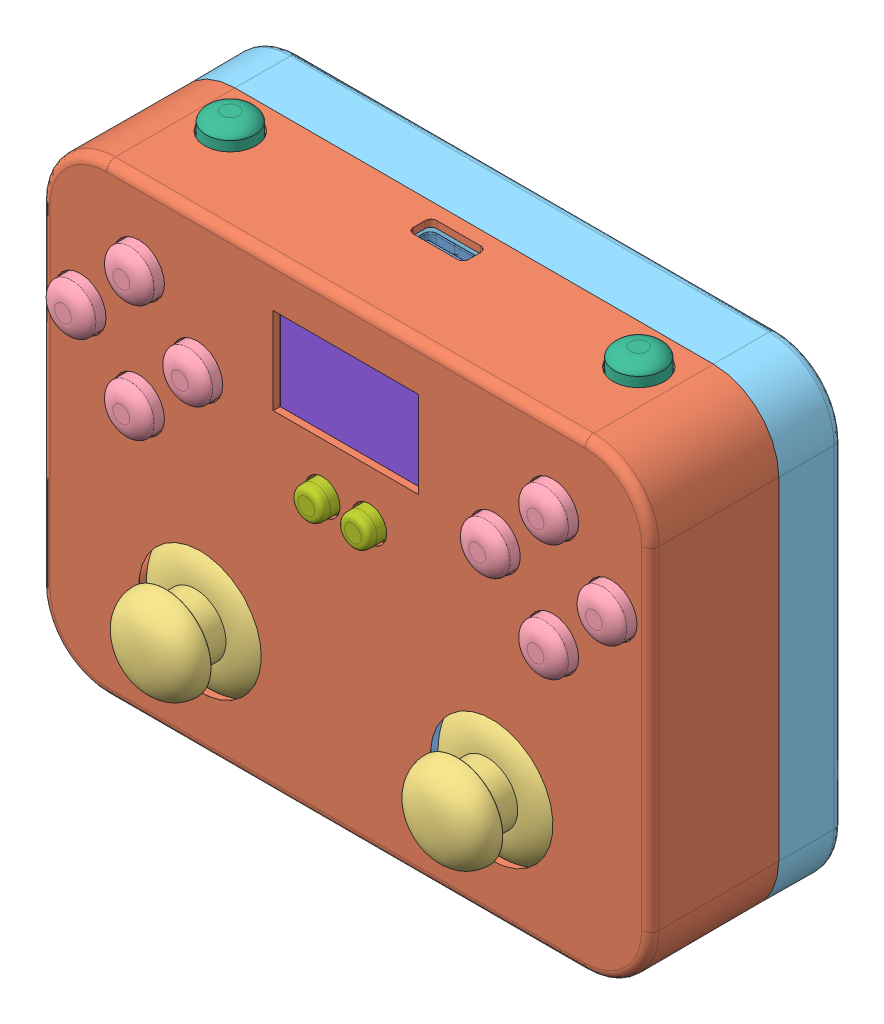
SolidWorks assembly 装配体2, configuration 默认. Lengths in mm.
Overall size (104.4 82.4 43.8).
18 component instances, 8 part files, 42 mates.
Components (placement in the parent):
- PCB2-1: PCB2 [默认] at (-22.2007 6.6699 94.0792) size (100.01 75.97 27.34)
- 上盖-1: 上盖 [默认] at (-22.2007 6.6699 113.2792) x (-1 0 0) z (0 -1 0) size (104.4 22.01 79.4)
- 摇杆-1: 摇杆 [Default] at (-47.2006 -16.3615 106.0792) x (-0.808062 -0.589097 0) z (0 0 1) size (26 26 18)
- 按钮-1: 按钮 [Default] at (-57.7007 30.6699 116.2792) x (-0.814442 0.580245 0) z (0 0 -1) size (11 8.3 17.2)
- 摇杆-2: 摇杆 [Default] at (2.7994 -16.3615 106.0792) x (0.828783 0.55957 0) z (0 0 1) size (26 26 18)
- 按钮-2: 按钮 [Default] at (13.2993 30.6699 116.2792) x (0 1 0) z (0 0 -1) size (11 8.3 17.2)
- 按钮-3: 按钮 [Default] at (-67.7007 20.6699 116.2792) x (-1 0 0) z (0 0 -1) size (11 8.3 17.2)
- 按钮-4: 按钮 [Default] at (13.2993 10.6699 116.2792) x (0 -1 0) z (0 0 -1) size (11 8.3 17.2)
- 按钮-5: 按钮 [Default] at (-57.7007 10.6699 116.2792) x (0 -1 0) z (0 0 -1) size (11 8.3 17.2)
- 按钮-6: 按钮 [Default] at (23.2993 20.6699 116.2792) x (-1 0 0) z (0 0 -1) size (11 8.3 17.2)
- 按钮-7: 按钮 [Default] at (-47.7007 20.6699 116.2792) x (-1 0 0) z (0 0 -1) size (11 8.3 17.2)
- 按钮-8: 按钮 [Default] at (3.2993 20.6699 116.2792) x (-1 0 0) z (0 0 -1) size (11 8.3 17.2)
- 后盖-1: 后盖 [默认] at (-22.2007 6.6699 80.2792) x (1 0 0) z (0 -1 0) size (104.4 12.2 79.4)
- 按钮2-1: 按钮2 [Default] at (12.7992 46.8699 98.0792) x (1 0 0) z (0 -1 0) size (13 8.3 5.4)
- 按钮2-3: 按钮2 [Default] at (-57.2006 46.8699 98.0792) x (0.990267 0 -0.139181) z (0 -1 0) size (13 8.3 5.4)
- 按钮3-1: 按钮3 [Default] at (-26.2007 12.6699 116.0792) x (0 -1 0) z (0 0 -1) size (8 5.4 17)
- 按钮3-4: 按钮3 [Default] at (-18.2007 12.6699 116.0792) x (0 -1 0) z (0 0 -1) size (8 5.4 17)
- 屏幕-1: 屏幕 [默认] at (-20.7557 28.6699 110.4792) x (0 1 0) z (0 0 1) size (17.6 31 1.6)
Mates (geometry in assembly coordinates):
- 平行1: parallel aligned: plane of 上盖-1 through (-63.2007 32.6699 113.2792) normal (0 0 1); plane of 按钮-1 through (-57.7007 30.6699 116.2792) normal (0 0 1)
- 距离4: distance = 3 mm aligned: plane of 按钮-1 through (-57.7007 30.6699 116.2792) normal (0 0 1); plane of 上盖-1 through (-63.2007 32.6699 113.2792) normal (0 0 1)
- 同心6: concentric anti-aligned: cylinder of 上盖-1 through (-57.7007 30.6699 122.0792) axis (0 0 -1) radius 4.4; cylinder of 按钮-1 through (-57.7007 30.6699 99.0792) axis (0 0 1) radius 4.15
- 同心7: concentric anti-aligned: cylinder of 上盖-1 through (13.2993 30.6699 122.0792) axis (0 0 -1) radius 4.4; cylinder of 按钮-2 through (13.2993 30.6699 99.0792) axis (0 0 1) radius 4.15
- 平行2: parallel anti-aligned: plane of 上盖-1 through (12.5493 36.2194 106.0792) normal (1 0 0); plane of 按钮-2 through (12.6993 36.1699 112.0792) normal (-1 0 0)
- 同心8: concentric anti-aligned: cylinder of 上盖-1 through (-67.7007 20.6699 122.0792) axis (0 0 -1) radius 4.4; cylinder of 按钮-3 through (-67.7007 20.6699 99.0792) axis (0 0 1) radius 4.15
- 同心9: concentric anti-aligned: cylinder of 上盖-1 through (-47.7007 20.6699 122.0792) axis (0 0 -1) radius 4.4; cylinder of 按钮-7 through (-47.7007 20.6699 99.0792) axis (0 0 1) radius 4.15
- 同心10: concentric anti-aligned: cylinder of 上盖-1 through (-57.7007 10.6699 122.0792) axis (0 0 -1) radius 4.4; cylinder of 按钮-5 through (-57.7007 10.6699 99.0792) axis (0 0 1) radius 4.15
- 平行7: parallel aligned: plane of 上盖-1 through (-2.2503 21.4199 106.0792) normal (0 -1 0); plane of 按钮-8 through (-2.2007 20.0699 112.0792) normal (0 -1 0)
- 同心14: concentric anti-aligned: cylinder of 上盖-1 through (3.2993 20.6699 122.0792) axis (0 0 -1) radius 4.4; cylinder of 按钮-8 through (3.2993 20.6699 99.0792) axis (0 0 1) radius 4.15
- 平行8: parallel aligned: plane of 上盖-1 through (12.5493 15.0055 106.0792) normal (1 0 0); plane of 按钮-4 through (13.8993 5.1699 112.0792) normal (1 0 0)
- 同心15: concentric anti-aligned: cylinder of 上盖-1 through (13.2993 10.6699 122.0792) axis (0 0 -1) radius 4.4; cylinder of 按钮-4 through (13.2993 10.6699 99.0792) axis (0 0 1) radius 4.15
- 平行9: parallel aligned: plane of 上盖-1 through (18.9637 21.4199 106.0792) normal (0 -1 0); plane of 按钮-6 through (17.7993 20.0699 112.0792) normal (0 -1 0)
- 同心16: concentric anti-aligned: cylinder of 上盖-1 through (23.2993 20.6699 122.0792) axis (0 0 -1) radius 4.4; cylinder of 按钮-6 through (23.2993 20.6699 99.0792) axis (0 0 1) radius 4.15
- 重合1: coincident anti-aligned: plane of PCB2-1 through (-57.7006 10.67 99.0792) normal (0 0 1); plane of 按钮-5 through (-57.7007 10.6699 99.0792) normal (0 0 -1)
- 重合2: coincident anti-aligned: plane of PCB2-1 through (-67.7006 20.67 99.0792) normal (0 0 1); plane of 按钮-3 through (-67.7007 20.6699 99.0792) normal (0 0 -1)
- 重合3: coincident anti-aligned: plane of PCB2-1 through (-57.7006 30.67 99.0792) normal (0 0 1); plane of 按钮-1 through (-57.7007 30.6699 99.0792) normal (0 0 -1)
- 同心17: concentric anti-aligned: cylinder of PCB2-1 through (-67.2007 36.6699 93.6678) axis (0 0 -1) radius 1.2; cylinder of 上盖-1 through (-67.2007 36.6699 94.0792) axis (0 0 1) radius 1
- 同心18: concentric anti-aligned: cylinder of PCB2-1 through (-67.2007 -23.3301 93.6678) axis (0 0 -1) radius 1.2; cylinder of 上盖-1 through (-67.2007 -23.3301 94.0792) axis (0 0 1) radius 1
- 距离8: distance = 12 mm anti-aligned: plane of PCB2-1 through (-72.2007 -19.3131 94.0792) normal (0 0 1); plane of 摇杆-1 through (-47.2006 -16.3615 106.0792) normal (0 0 -1)
- 同心19: concentric aligned: cylinder of PCB2-1 through (-47.2006 -16.3615 94.0792) axis (0 0 -1) radius 2; cylinder of 摇杆-1 through (-47.2006 -16.3615 119.0792) axis (0 0 -1) radius 5.25
- 距离9: distance = 12 mm anti-aligned: plane of PCB2-1 through (-72.2007 -19.3131 94.0792) normal (0 0 1); plane of 摇杆-2 through (2.7994 -16.3615 106.0792) normal (0 0 -1)
- 重合4: coincident anti-aligned: plane of PCB2-1 through (-47.7006 20.67 99.0792) normal (0 0 1); plane of 按钮-7 through (-47.7007 20.6699 99.0792) normal (0 0 -1)
- 重合5: coincident anti-aligned: plane of PCB2-1 through (3.2994 20.67 99.0792) normal (0 0 1); plane of 按钮-8 through (3.2993 20.6699 99.0792) normal (0 0 -1)
- 平行11: parallel aligned: plane of 上盖-1 through (18.7993 43.8699 91.2792) normal (0 1 0); plane of 按钮2-1 through (12.7992 46.8699 98.0792) normal (0 1 0)
- 距离10: distance = 3 mm aligned: plane of 按钮2-1 through (12.7992 46.8699 98.0792) normal (0 1 0); plane of 上盖-1 through (18.7993 43.8699 91.2792) normal (0 1 0)
- 平行12: parallel anti-aligned: plane of PCB2-1 through (-72.2007 -19.3131 94.0792) normal (0 0 1); plane of 按钮2-1 through (19.2992 42.6699 94.3292) normal (0 0 -1)
- 重合7: coincident anti-aligned: plane of 上盖-1 through (-63.2007 42.6699 91.2792) normal (0 -1 0); plane of 按钮2-3 through (-57.2006 42.6699 98.0792) normal (0 1 0)
- 同心23: concentric aligned: circle of 上盖-1; cylinder of 按钮3-1 through (-26.2007 12.6699 99.0792) axis (0 0 1) radius 2.65
- 平行13: parallel aligned: plane of 上盖-1 through (-27.4507 15.3971 106.0792) normal (1 0 0); plane of 按钮3-1 through (-25.6007 8.6699 112.0792) normal (1 0 0)
- 平行14: parallel anti-aligned: plane of 上盖-1 through (-16.9507 15.3971 106.0792) normal (-1 0 0); plane of 按钮3-4 through (-17.6007 8.6699 112.0792) normal (1 0 0)
- 同心24: concentric anti-aligned: cylinder of 上盖-1 through (-18.2007 12.6699 122.0792) axis (0 0 -1) radius 3; cylinder of 按钮3-4 through (-18.2007 12.6699 99.0792) axis (0 0 1) radius 2.65
- 重合9: coincident anti-aligned: plane of PCB2-1 through (-18.2006 12.653 99.0792) normal (0 0 1); plane of 按钮3-4 through (-18.2007 12.6699 99.0792) normal (0 0 -1)
- 距离11: distance = 1.6 mm anti-aligned: plane of 上盖-1 through (22.7993 36.6699 94.0792) normal (0 0 -1); plane of 后盖-1 through (22.7993 36.6699 92.4792) normal (0 0 1)
- 同心25: concentric anti-aligned: cylinder of 上盖-1 through (22.7993 36.6699 94.0792) axis (0 0 1) radius 1; cylinder of 后盖-1 through (22.7993 36.6699 92.4792) axis (0 0 -1) radius 2.4
- 同心26: concentric anti-aligned: cylinder of 上盖-1 through (-67.2007 36.6699 94.0792) axis (0 0 1) radius 1; cylinder of 后盖-1 through (-67.2007 36.6699 92.4792) axis (0 0 -1) radius 2.4
- 重合10: coincident anti-aligned: plane of PCB2-1 through (-26.2006 12.653 99.0792) normal (0 0 1); plane of 按钮3-1 through (-26.2007 12.6699 99.0792) normal (0 0 -1)
- 重合11: coincident anti-aligned: plane of 上盖-1 through (-63.2007 32.6699 112.0792) normal (0 0 -1); plane of 屏幕-1 through (-20.7557 28.6699 112.0792) normal (0 0 1)
- 平行15: parallel: plane of 上盖-1 through (-9.7457 36.0999 103.2792) normal (0 -1 0); line of 屏幕-1 through (-9.7457 36.0999 112.0792) axis (-1 0 0)
- 重合12: coincident aligned: plane of 上盖-1 through (-9.7457 36.0999 103.2792) normal (0 -1 0); plane of 屏幕-1 through (-9.7457 36.0999 112.0692) normal (0 -1 0)
- 重合13: coincident aligned: plane of 上盖-1 through (-9.7457 21.2399 103.2792) normal (-1 0 0); plane of 屏幕-1 through (-9.7457 21.2399 112.0692) normal (-1 0 0)
- 同心27: concentric aligned: cylinder of PCB2-1 through (2.7994 -16.3615 94.0792) axis (0 0 -1) radius 2; circle of 摇杆-2
